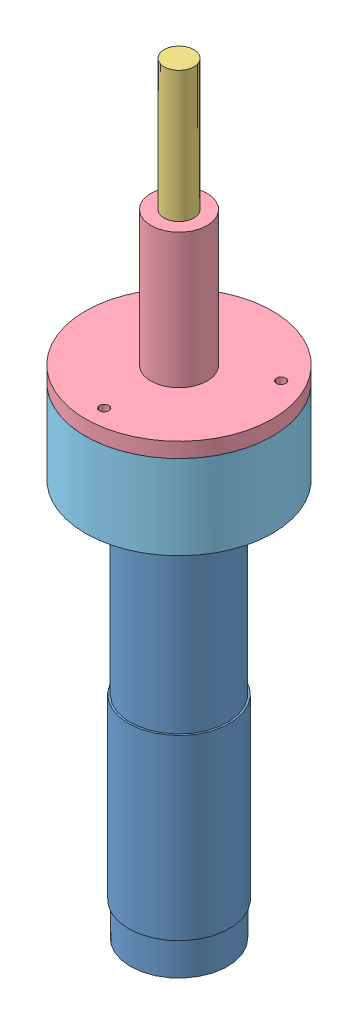
SolidWorks assembly Assem1, configuration Default. Lengths in mm.
Overall size (100 407.5 100).
5 component instances, 5 part files, 16 mates.
Components (placement in the parent):
- steering motor-1: steering motor [Default] at (-42.7198 -68.3039 0.4993) size (54 237.5 54)
- Motor connector-1: Motor connector [Default] at (-42.7198 151.1961 0.4993) x (-1 0 0) z (0 1 0) size (50 50 10)
- Drive shaft-1: Drive shaft [Default] at (-42.7198 151.1961 0.4993) x (-1 0 0) z (0 1 0) size (55 55 170)
- Shaft bracket-1: Shaft bracket [Default] at (-42.7198 161.1961 0.4993) x (-1 0 0) z (0 1 0) size (100 100 80)
- Motor bracket-1: Motor bracket [Default] at (-42.7198 126.1961 0.4993) x (-1 0 0) z (0 1 0) size (100 100 45)
Mates (geometry in assembly coordinates):
- InPlace1: in place: plane of steering motor-1 through (-42.7198 151.1961 0.4993) normal (0 1 0); plane of ? through (0 151.1961 0) normal (0 1 0); moOrthogonalPlaneRef_w of steering motor-1 through (-42.7198 151.1961 0.4993) normal (0 1 0); unknown of ?; plane of steering motor-1 through (-42.7198 151.1961 0.4993) normal (0 1 0); line of ? through (-55 0 151.1961) axis (0 -1 0); plane of steering motor-1 through (-42.7198 151.1961 0.4993) normal (0 1 0); unknown of ?
- Coincident1: coincident aligned: plane of ?; plane of ?
- Coincident2: coincident aligned: moOrthogonalPlaneRef_w of steering motor-1 through (-42.7198 151.1961 0.4993) normal (0 0 1); plane of ?
- Coincident3: coincident anti-aligned: moOrthogonalPlaneRef_w of steering motor-1 through (-42.7198 151.1961 0.4993) normal (1 0 0); plane of ?
- InPlace2: in place: plane of ? through (-42.7198 151.1961 0.4993) normal (0 1 0); plane of ? through (0 151.1961 0) normal (0 1 0); plane of ? through (-42.7198 151.1961 0.4993) normal (0 1 0); unknown of ?; plane of ? through (-42.7198 151.1961 0.4993) normal (0 1 0); line of ? through (-55 0 151.1961) axis (0 -1 0); plane of ? through (-42.7198 151.1961 0.4993) normal (0 1 0); unknown of ?
- Coincident4: coincident aligned: plane of ?; plane of ?
- Coincident5: coincident aligned: moOrthogonalPlaneRef_w of ? through (-42.7198 151.1961 0.4993) normal (0 0 1); plane of ?
- Coincident6: coincident anti-aligned: moOrthogonalPlaneRef_w of ? through (-42.7198 151.1961 0.4993) normal (1 0 0); plane of ?
- InPlace3: in place: plane of ? through (-42.7198 161.1961 0.4993) normal (0 1 0); plane of ? through (0 161.1961 0) normal (0 1 0); plane of ? through (-42.7198 161.1961 0.4993) normal (0 1 0); unknown of ?; plane of ? through (-42.7198 161.1961 0.4993) normal (0 1 0); line of ? through (-55 0 161.1961) axis (0 -1 0); plane of ? through (-42.7198 161.1961 0.4993) normal (0 1 0); unknown of Shaft bracket-1
- Coincident7: coincident aligned: plane of ?; plane of ?
- Coincident8: coincident aligned: moOrthogonalPlaneRef_w of ? through (-42.7198 161.1961 0.4993) normal (0 0 1); plane of Shaft bracket-1
- Coincident9: coincident anti-aligned: moOrthogonalPlaneRef_w of ? through (-42.7198 161.1961 0.4993) normal (1 0 0); plane of Shaft bracket-1
- InPlace4: in place: plane of steering motor-1 through (-42.7198 126.1961 0.4993) normal (0 1 0); plane of ? through (0 126.1961 0) normal (0 1 0); plane of steering motor-1 through (-42.7198 126.1961 0.4993) normal (0 1 0); unknown of ?; plane of steering motor-1 through (-42.7198 126.1961 0.4993) normal (0 1 0); line of ? through (-55 0 126.1961) axis (0 -1 0); plane of steering motor-1 through (-42.7198 126.1961 0.4993) normal (0 1 0); unknown of Motor bracket-1
- Coincident10: coincident aligned: plane of ?; plane of ?
- Coincident11: coincident aligned: moOrthogonalPlaneRef_w of steering motor-1 through (-42.7198 126.1961 0.4993) normal (0 0 1); plane of Motor bracket-1
- Coincident12: coincident anti-aligned: moOrthogonalPlaneRef_w of steering motor-1 through (-42.7198 126.1961 0.4993) normal (1 0 0); plane of steering motor-1
